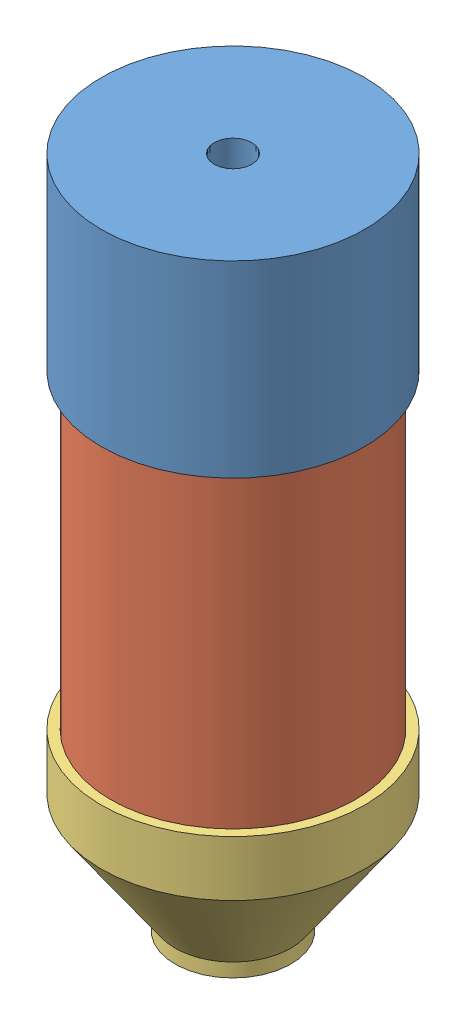
SolidWorks assembly Assem1, configuration Default. Lengths in mm.
Overall size (100.32 227.2 100.32).
3 component instances, 3 part files, 5 mates.
Components (placement in the parent):
- APL_PME_PVCdome-1: APL_PME_PVCdome [Default] at origin size (88.9 63.5 88.9)
- APL_PME_PVCchamber-1: APL_PME_PVCchamber [Default] at (0 -117.475 0) x (0.997983 0 -0.063479) z (0.063479 0 0.997983) size (82.55 152.4 82.55)
- APL_PME_nozzleForPVC-1: APL_PME_nozzleForPVC [Default] at (0 -104.775 0) x (0 -1 0) z (-0.137997 0 0.990433) size (58.92 88.9 88.9)
Mates (geometry in assembly coordinates):
- Coincident1: coordinate: point of APL_PME_PVCdome-1
- Concentric1: concentric aligned: cylinder of APL_PME_PVCdome-1 through (0 0 0) axis (0 -1 0) radius 41.275; cylinder of APL_PME_PVCchamber-1 through (0 -117.475 0) axis (0 -1 0) radius 41.275
- Distance1: distance = 25.4 mm anti-aligned: plane of APL_PME_PVCdome-1 through (-41.275 60.325 0) normal (0 -1 0); plane of APL_PME_PVCchamber-1 through (-38.0232 34.925 2.4185) normal (0 1 0)
- Concentric2: concentric anti-aligned: cylinder of APL_PME_PVCchamber-1 through (0 -117.475 0) axis (0 -1 0) radius 38.1; cylinder of APL_PME_nozzleForPVC-1 through (0 -104.775 0) axis (0 1 0) radius 41.275
- Coincident2: coincident anti-aligned: plane of APL_PME_PVCchamber-1 through (-41.1918 -117.475 2.6201) normal (0 -1 0); plane of APL_PME_nozzleForPVC-1 through (40.8801 -117.475 5.6958) normal (0 1 0)
